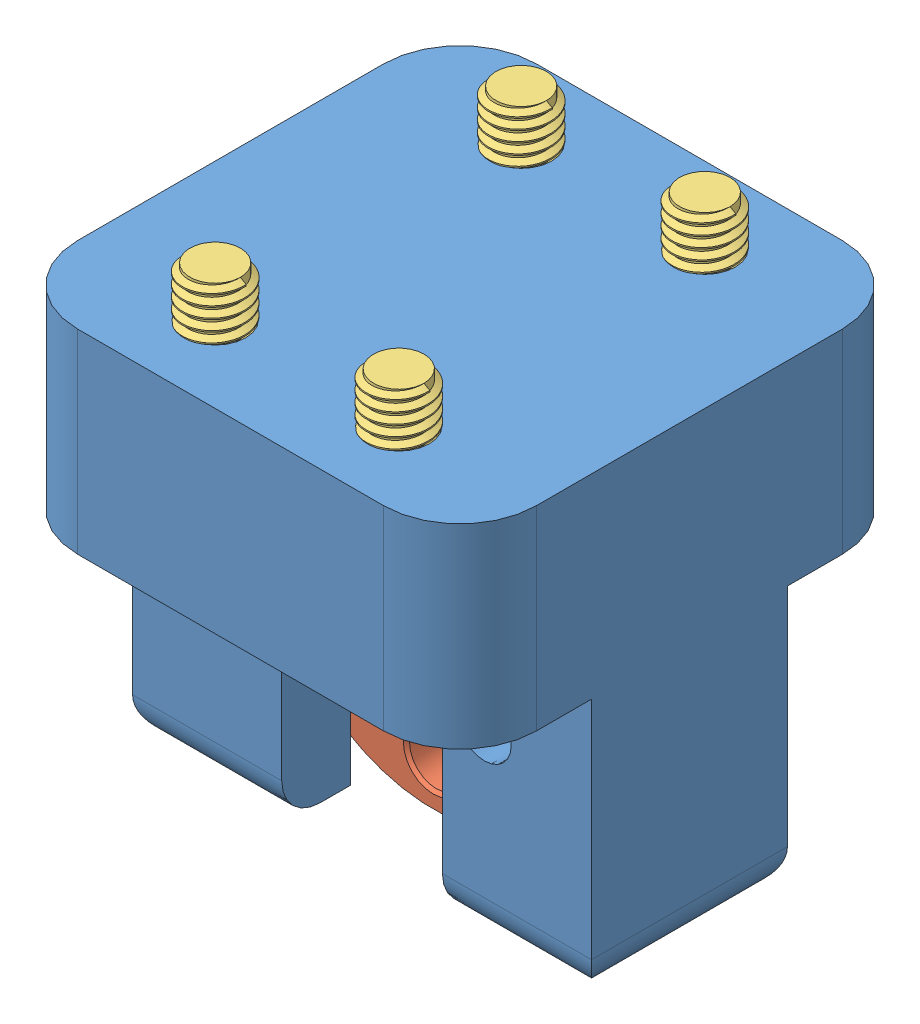
SolidWorks assembly TR8_nut_assembly, configuration Default. Lengths in mm.
Overall size (30 33.25 30).
6 component instances, 3 part files, 0 mates.
Components (placement in the parent):
- TR8_holder-1: TR8_holder [Default] at origin size (30 30 30)
- TR8_lead_screw-1: TR8_lead_screw [Default] at (0 12 1.75) size (22 22 16.4)
- M4x14_PH-1: M4x14_PH [Default] at (6 19.25 -10) x (1 0 0) z (0 0 -1) size (6 16.66 6)
- M4x14_PH-2: M4x14_PH [Default] at (-6 19.25 -10) x (1 0 0) z (0 0 -1) size (6 16.66 6)
- M4x14_PH-3: M4x14_PH [Default] at (6 19.25 10) x (1 0 0) z (0 0 -1) size (6 16.66 6)
- M4x14_PH-4: M4x14_PH [Default] at (-6 19.25 10) x (1 0 0) z (0 0 -1) size (6 16.66 6)
